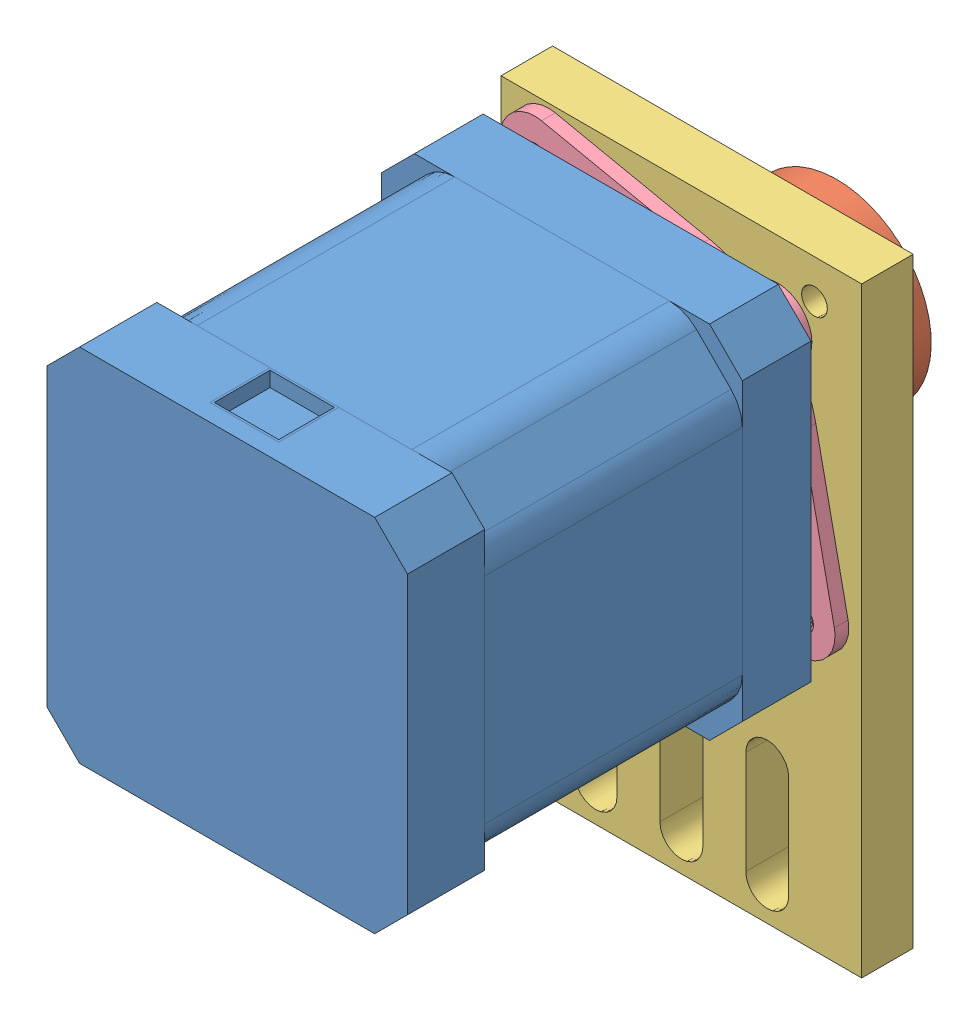
SolidWorks assembly y-bracket, configuration Default. Lengths in mm.
Overall size (93.79 93.79 71).
4 component instances, 4 part files, 8 mates.
Components (placement in the parent):
- NEMA17_48-1: NEMA17_48 [Default] at (11.6367 44.9381 35.5117) x (-1 0 0) z (0 0 -1) size (42 42 71)
- GT2 Pulley-1: GT2 Pulley [Default] at (11.6367 44.9381 21.5117) x (-0.999479 -0.032284 0) z (-0.032284 0.999479 0) size (22 17 22)
- Z Stepper Mount-1: Z Stepper Mount [Default] at (11.6367 29.9381 23.6117) x (1 0 0) z (0 -1 0) size (42 6 70)
- Stepper Damper-1: Stepper Damper [Default] at (11.6365 44.9378 35.5117) x (0.707107 -0.707107 0) z (0.707107 0.707107 0) size (51.85 6.11 80.79)
Mates (geometry in assembly coordinates):
- Concentric3: concentric anti-aligned: cylinder of NEMA17_48-1 through (11.6367 44.9381 11.5117) axis (0 0 1) radius 2.5; cylinder of GT2 Pulley-1 through (11.6367 44.9381 31.5117) axis (0 0 -1) radius 2.5
- Concentric7: concentric aligned: cylinder of NEMA17_48-1 through (27.1367 29.4381 40.0117) axis (0 0 -1) radius 1.5; cylinder of Z Stepper Mount-1 through (27.1367 29.4381 29.6117) axis (0 0 -1) radius 1.55
- Concentric8: concentric aligned: cylinder of NEMA17_48-1 through (-3.8633 60.4381 40.0117) axis (0 0 -1) radius 1.5; cylinder of Z Stepper Mount-1 through (-3.8633 60.4381 29.6117) axis (0 0 -1) radius 1.55
- Coincident4: coincident aligned: plane of NEMA17_48-1 through (11.6367 44.9381 11.5117) normal (0 0 -1); plane of GT2 Pulley-1 through (11.6367 44.9381 11.5117) normal (0 0 -1)
- Coincident5: coincident anti-aligned: plane of NEMA17_48-1 through (11.6367 44.9381 35.5117) normal (0 0 -1); plane of Stepper Damper-1 through (11.6365 44.9378 35.5117) normal (0 0 1)
- Concentric9: concentric anti-aligned: cylinder of NEMA17_48-1 through (-3.8633 29.4381 40.0117) axis (0 0 -1) radius 1.5; cylinder of Stepper Damper-1 through (-3.8633 29.4381 35.5117) axis (0 0 1) radius 1.75
- Concentric10: concentric anti-aligned: cylinder of NEMA17_48-1 through (27.1367 60.4381 40.0117) axis (0 0 -1) radius 1.5; cylinder of Stepper Damper-1 through (27.1363 60.4376 35.5117) axis (0 0 1) radius 1.75
- Coincident7: coincident: plane of Z Stepper Mount-1 through (11.6367 29.9381 29.6117) normal (0 0 1); line of Stepper Damper-1 through (-3.0448 64.353 29.6117) axis (0.978839 -0.204634 0)
